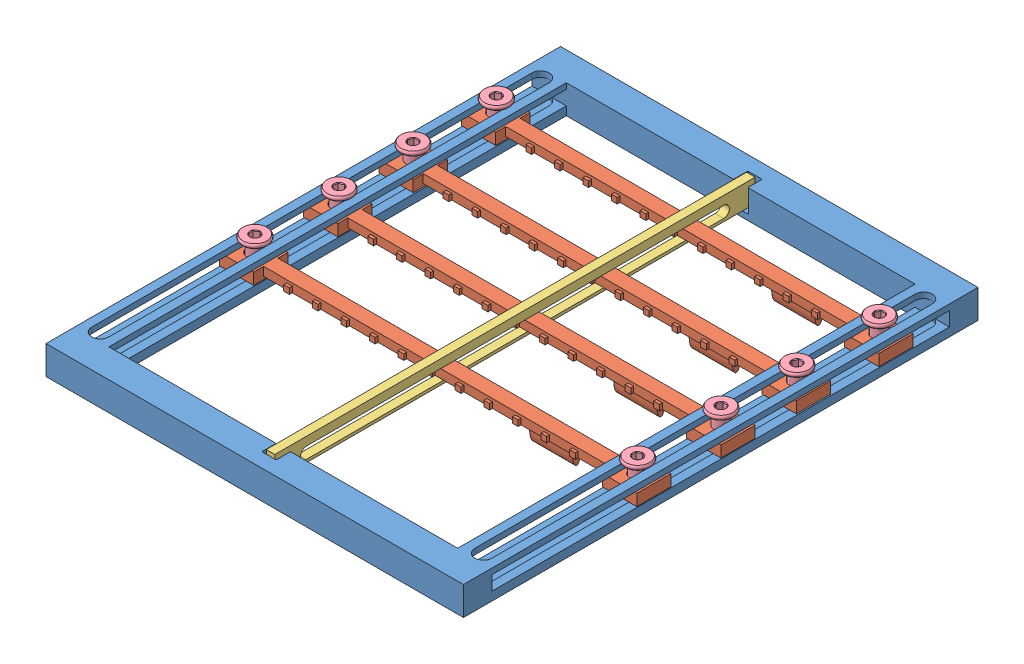
SolidWorks assembly tray_assembly, configuration Default. Lengths in mm.
Overall size (146.38 15.08 180).
15 component instances, 5 part files, 0 mates.
Components (placement in the parent):
- main4-1: main4 [Default] at (-11.052 63.9614 248.579) size (146 12 180)
- holder-1: holder [Default] at (141.5288 68.3895 100.5272) x (0 0 -1) z (1 0 0) size (12 8 146)
- holder-5: holder [Default] at (141.3175 68.3127 129.1759) x (0 0 -1) z (1 0 0) size (12 8 146)
- holder-6: holder [Default] at (141.4934 68.2835 155.7234) x (0 0 -1) z (1 0 0) size (12 8 146)
- holder-7: holder [Default] at (141.3954 68.197 185.0617) x (0 0 -1) z (1 0 0) size (12 8 146)
- Part1^tray_assembly-1: Part1^tray_assembly [Default] at origin (virtual)
- middlebar-1: middlebar [Default] at (60.3794 64.5124 240.7647) size (3 8 168)
- Low Profile Screw M5-7: Low Profile Screw M5 [M5 x 10] at (7.7623 65.1718 90.9129) x (0 -1 0) z (-1 0 0) size (11.5 9 9)
- Low Profile Screw M5-8: Low Profile Screw M5 [M5 x 10] at (6.934 65.0753 119.2377) x (0 -1 0) z (0.924225 0 0.381849) size (11.5 9 9)
- Low Profile Screw M5-9: Low Profile Screw M5 [M5 x 10] at (7.9104 65.3361 146.0896) x (0 -1 0) z (-0.383049 0 -0.923728) size (11.5 9 9)
- Low Profile Screw M5-10: Low Profile Screw M5 [M5 x 10] at (7.547 65.3088 175.1607) x (0 -1 0) z (-1 0 0) size (11.5 9 9)
- Low Profile Screw M5-11: Low Profile Screw M5 [M5 x 10] at (141.2705 64.9516 175.0085) x (0 -1 0) z (1 0 0) size (11.5 9 9)
- Low Profile Screw M5-12: Low Profile Screw M5 [M5 x 10] at (141.2705 65.5408 145.8447) x (0 -1 0) z (0 0 1) size (11.5 9 9)
- Low Profile Screw M5-13: Low Profile Screw M5 [M5 x 10] at (141.2705 65.2462 119.3321) x (0 -1 0) z (0 0 1) size (11.5 9 9)
- Low Profile Screw M5-14: Low Profile Screw M5 [M5 x 10] at (141.2705 65.5408 90.4628) x (0 -1 0) z (0 0 1) size (11.5 9 9)
